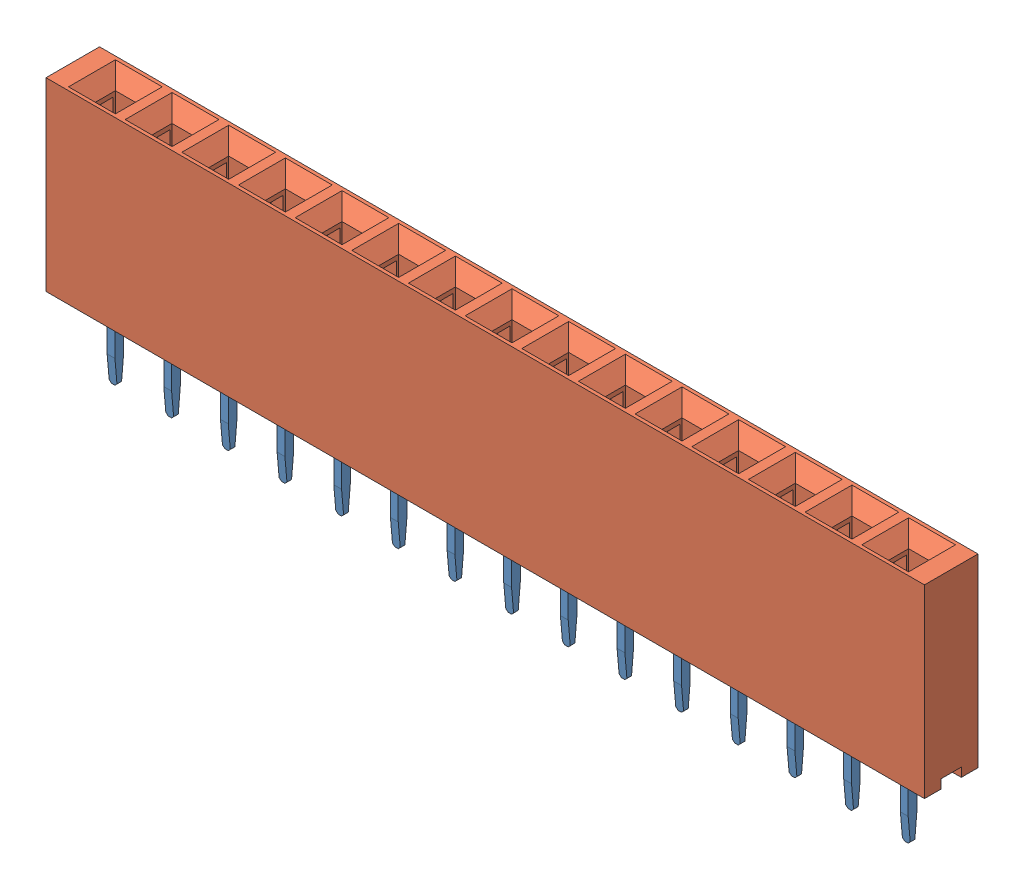
SolidWorks assembly 2_54_x_15_pitch_connector_, configuration Default. Lengths in mm.
Overall size (39.38 11.5 2.4).
2 component instances, 2 part files, 8 mates.
Components (placement in the parent):
- Pitch_x_15-1: Pitch_x_15 [Default] at origin size (37.51 8.86 0.39)
- Plastic_x_15-1: Plastic_x_15 [Default] x (1 0 0) z (0 1 0) size (39.38 2.4 8.3)
Mates (geometry in assembly coordinates):
- На месте1: in place: plane of Pitch_x_15-1 through (0 0 0) normal (0 0 1); moOrthogonalPlaneRef_w of Pitch_x_15-1 through (0 0 0) normal (0 1 0); plane of Pitch_x_15-1 through (0 0 0) normal (1 0 0); unknown of Pitch_x_15-1
- Совпадение1: coincident aligned: 
- Совпадение2: coincident aligned: plane of Pitch_x_15-1 through (0 0 0) normal (0 1 0)
- Совпадение3: coincident anti-aligned: plane of Pitch_x_15-1 through (0 0 0) normal (1 0 0)
- На месте2: in place: plane of Plastic_x_15-1 through (0 0 0) normal (0 1 0); plane of Plastic_x_15-1 through (0 0 0) normal (0 0 -1); plane of Plastic_x_15-1 through (0 0 0) normal (1 0 0); unknown of Plastic_x_15-1
- Совпадение4: coincident aligned: 
- Совпадение5: coincident aligned: plane of Plastic-1 through (0 0 0) normal (0 0 -1)
- Совпадение6: coincident anti-aligned: plane of Plastic-1 through (0 0 0) normal (1 0 0)
